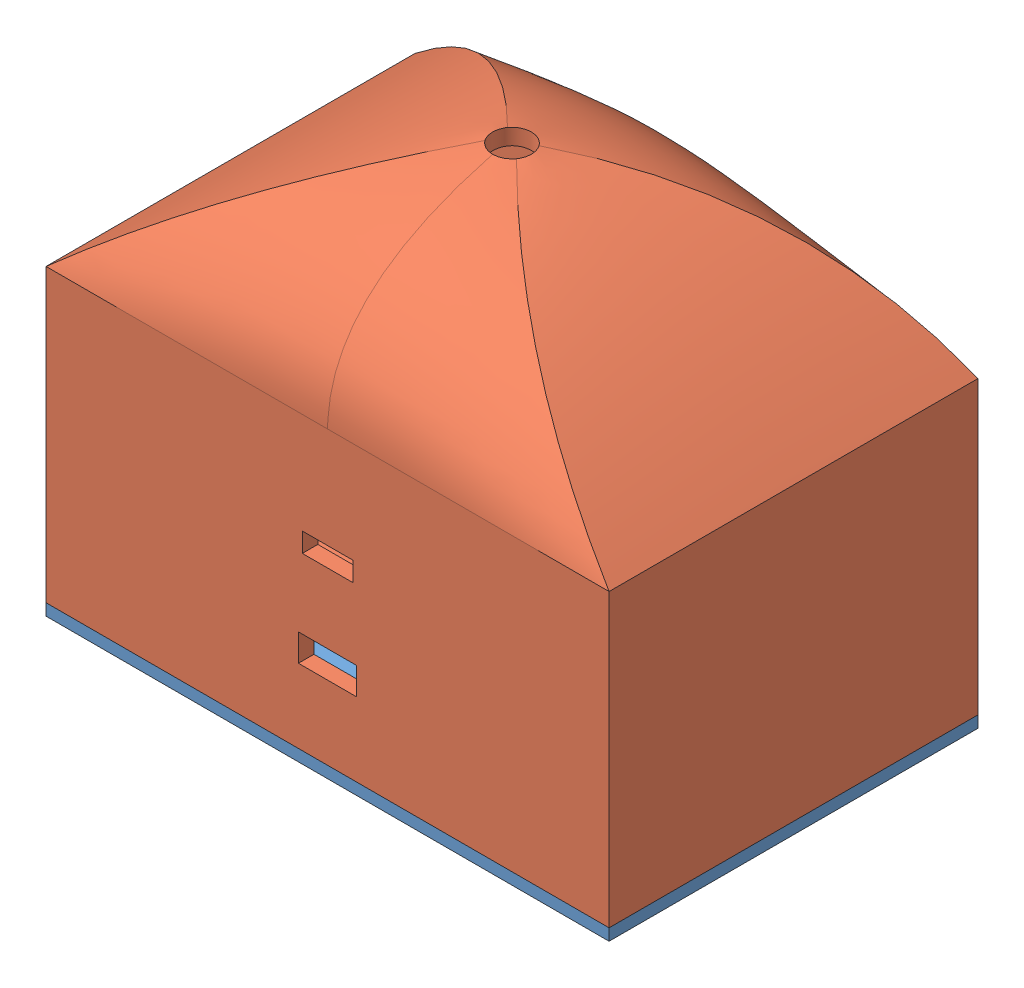
SolidWorks assembly Montagem, configuration Valor predeterminado. Lengths in mm.
Overall size (150 118 100).
2 component instances, 2 part files, 3 mates.
Components (placement in the parent):
- base-1: base [Valor predeterminado] at (-83.205 76.4102 81.4056) x (1 0 0) z (0 -1 0) size (150 100 18)
- topo-2: topo [Valor predeterminado] at (-76.705 76.4102 174.9056) x (1 0 0) z (0 1 0) size (145 95 115)
Mates (geometry in assembly coordinates):
- Largura1: width anti-aligned: plane of topo-2 through (-76.705 151.4102 174.9056) normal (1 0 0); plane of topo-2 through (60.295 151.4102 174.9056) normal (-1 0 0); plane of base-1 through (-75.705 82.4102 81.4056) normal (-1 0 0); plane of base-1 through (59.295 82.4102 81.4056) normal (1 0 0)
- Largura2: width anti-aligned: plane of base-1 through (-83.205 82.4102 173.9056) normal (0 0 1); plane of base-1 through (-83.205 82.4102 88.9056) normal (0 0 -1); plane of topo-2 through (-76.705 151.4102 174.9056) normal (0 0 -1); plane of topo-2 through (-76.705 151.4102 87.9056) normal (0 0 1)
- Coincidente1: coincident anti-aligned: plane of base-1 through (-83.205 76.4102 81.4056) normal (0 1 0); plane of topo-2 through (-76.705 76.4102 174.9056) normal (0 -1 0)
